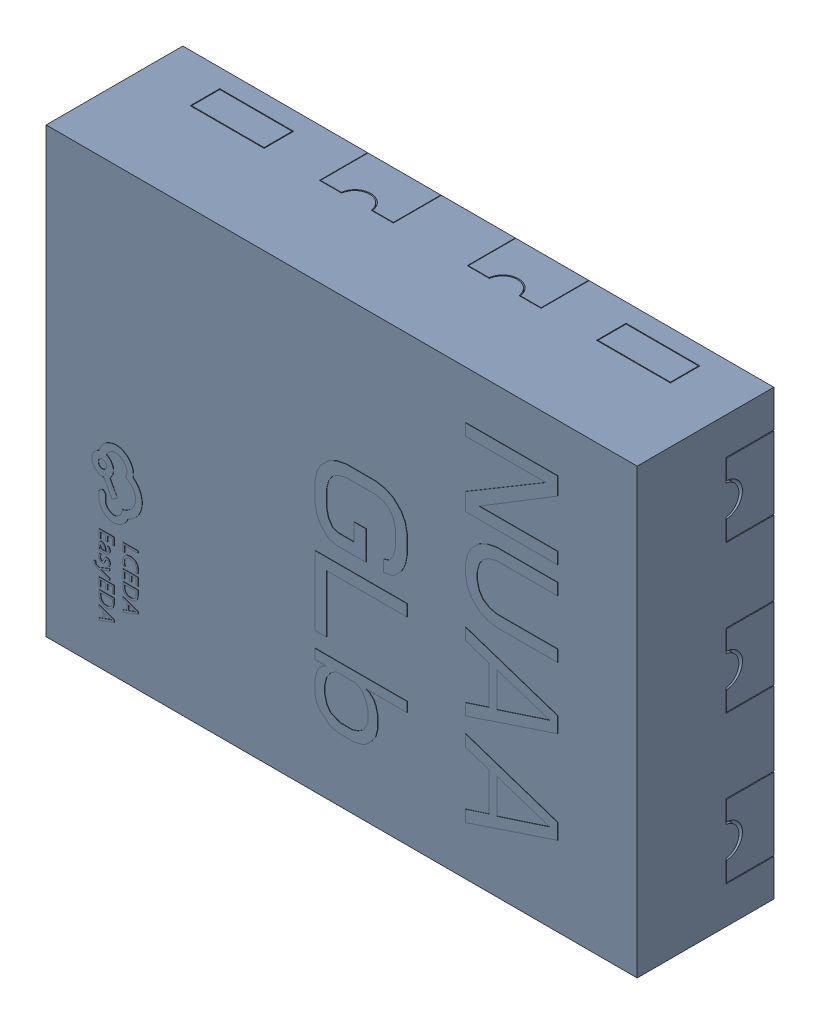
SolidWorks assembly FUSB301TMX, configuration Défaut. Lengths in mm.
Overall size (1.6 1.2 0.38).
3 component instances, 1 part files, 0 mates.
Components (placement in the parent):
- U1.step_988-1: U1.step_988 [Défaut] at (5.0775 -6.7805 1.6001) size (1.6 1.2 0.38)
  - TMLP-10_L1.6-W1.2-P0.40.step-1: TMLP-10_L1.6-W1.2-P0.40.step [Défaut] at origin size (1.6 1.2 0.38)
    - SOLID.step_990-1: SOLID.step_990 [Défaut] at origin size (1.6 1.2 0.38)
